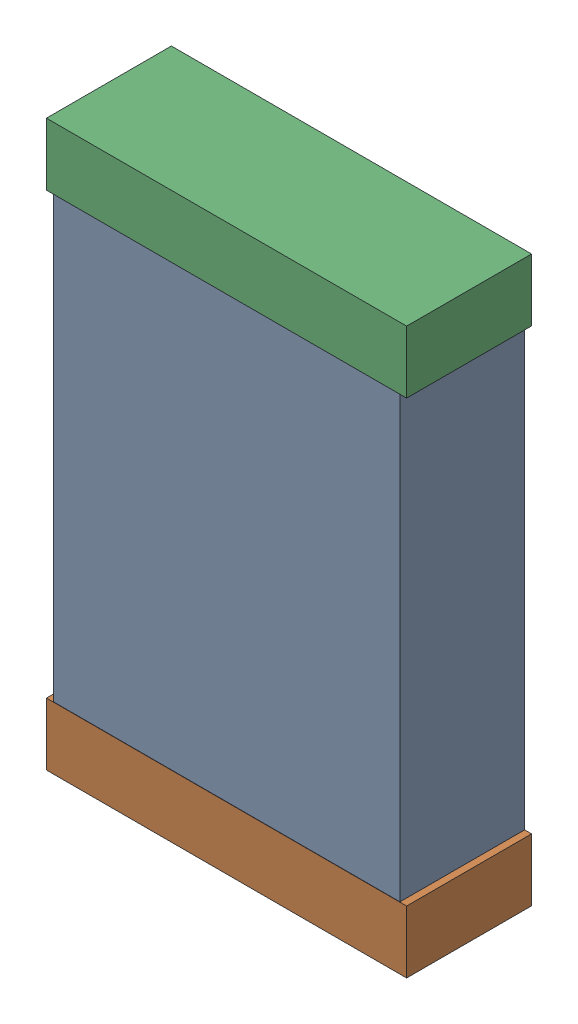
SolidWorks assembly C3, configuration Default. Lengths in mm.
Overall size (1.3 2.04 0.45).
6 component instances, 2 part files, 0 mates.
Components (placement in the parent):
- 740904480-1: 740904480 [Default] at (76.3008 2.8426 0) size (1.25 2 0.45)
  - Extruded_34-1: Extruded_34 [Default] at origin size (1.25 2 0.45)
- 740902240-1: 740902240 [Default] at (76.3008 1.9301 0) size (1.3 0.23 0.45)
  - Extruded_35-1: Extruded_35 [Default] at origin size (1.3 0.23 0.45)
- 740902240-2: 740902240 [Default] at (76.3008 3.7426 0) size (1.3 0.23 0.45)
  - Extruded_35-1: Extruded_35 [Default] at origin size (1.3 0.23 0.45)
